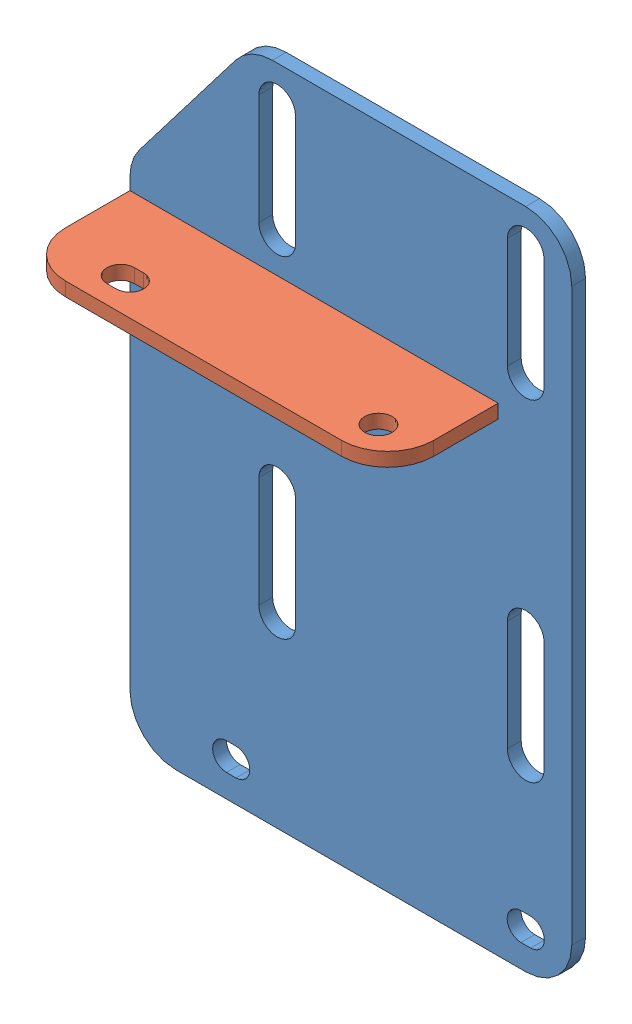
SolidWorks assembly Assem1, configuration Default. Lengths in mm.
Overall size (152.4 228.6 42.86).
2 component instances, 2 part files, 3 mates.
Components (placement in the parent):
- Part1-1: Part1 [Default] at origin size (152.4 228.6 4.76)
- York Bracket Flange-1: York Bracket Flange [Default] at (0 165.1 4.7625) x (1 0 0) z (0 -1 0) size (127 38.1 4.76)
Mates (geometry in assembly coordinates):
- Coincident1: coincident: plane of Part1-1 through (0 165.1 4.7371) normal (0 -1 0); plane of York Bracket Flange-1 through (0 165.1 4.7625) normal (0 1 0)
- Coincident2: coincident: plane of Part1-1 through (0 0 4.7625) normal (0 0 1); plane of York Bracket Flange-1 through (0 160.3375 4.7625) normal (0 0 -1)
- Coincident3: coincident aligned: plane of Part1-1 through (0 0 4.7625) normal (-1 0 0); plane of York Bracket Flange-1 through (0 160.3375 4.7625) normal (-1 0 0)
